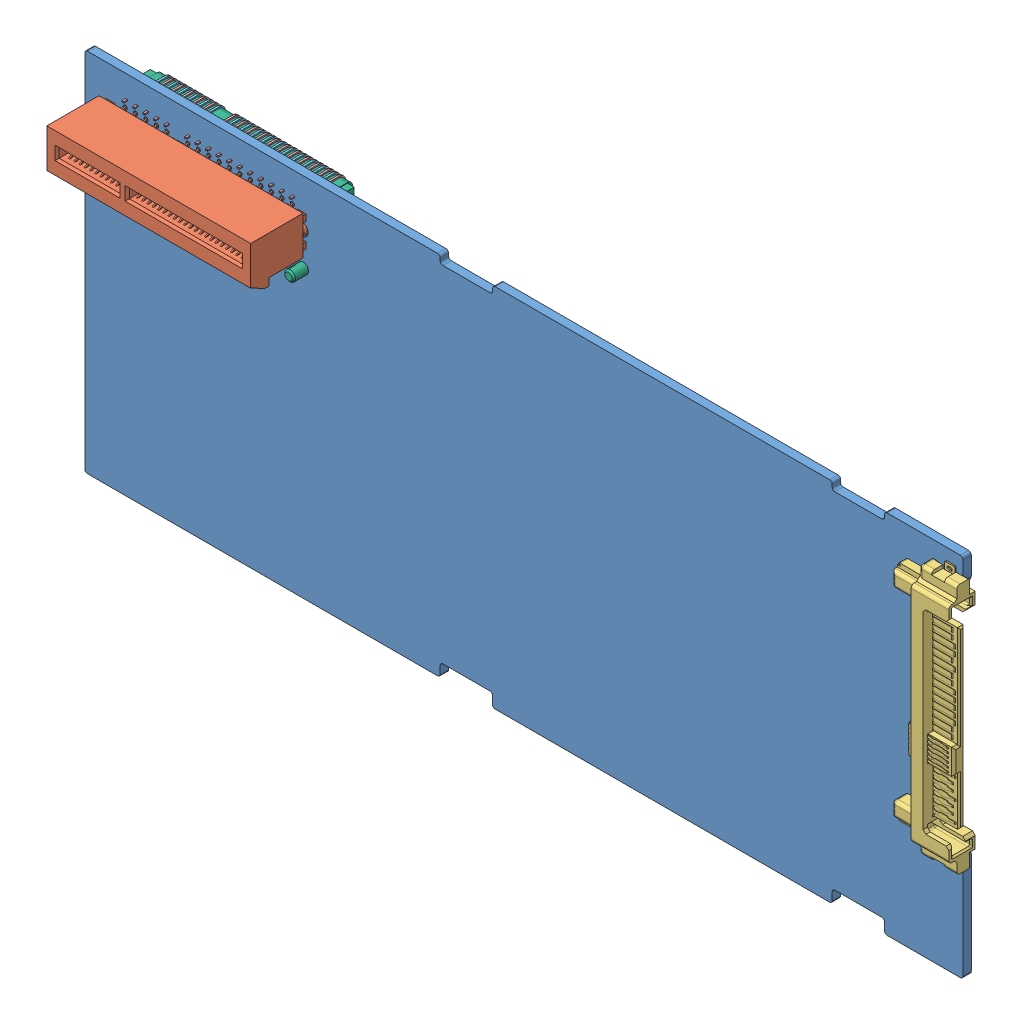
SolidWorks assembly u2CEM, configuration Default. Lengths in mm.
Overall size (169.53 63.5 22.05).
8 component instances, 6 part files, 9 mates.
Components (placement in the parent):
- u2CEM.step-1: u2CEM.step [Default] at origin size (168 63.5 1.6)
  - u2CEM PCB.step-1: u2CEM PCB.step [Default] at origin size (168 63.5 1.6)
- 10018783-x0xxx_64c.stp-1: 10018783-x0xxx_64c.stp [Default] at (230.235 -98.95 1.6) x (1 0.000053 0) z (0.000053 -1 0) size (39 15.4 8.8)
- 3d_model_psas4m213002xxx.stp-1: 3d_model_psas4m213002xxx.stp [Default] at (374.1 -116.95 3.6) x (0 1 0) z (0 0 -1) size (49.45 12.58 5.15)
- PCIE_064_02_F_D_RA-1: PCIE_064_02_F_D_RA [Default] at (235.4948 -101.7998 -5.8) x (-1 -0.000053 0) z (0 0 1) size (39.03 18.85 13.86)
  - PCIE_064_02_F_D_RA_3-1: PCIE_064_02_F_D_RA_3 [Default] at (6.9945 0 0) size (34 17.93 10.46)
  - PCIE_064_02_F_D_RA_5-1: PCIE_064_02_F_D_RA_5 [Default] at (6.9945 0 0) size (34 16.93 10.48)
  - PCIE_064_02_F_D_RA_7-1: PCIE_064_02_F_D_RA_7 [Default] at origin size (39.03 18.85 13.86)
Mates (geometry in assembly coordinates):
- Concentric1: concentric: cylinder of 10018783-x0xxx_64c.stp-1 through (230.385 -98.95 11.8728) axis (0 0 -1) radius 1.1; cylinder of u2CEM.step-1/u2CEM PCB.step-1 through (230.385 -98.95 -0.8) axis (0 0 1) radius 1.2
- Parallel1: parallel: plane of u2CEM.step-1/u2CEM PCB.step-1 through (212.5 -90 0) normal (-0.000053 1 0); plane of 10018783-x0xxx_64c.stp-1 through (235.2352 -102.6497 7.6) normal (0.000053 -1 0)
- Coincident1: coincident: plane of u2CEM.step-1/u2CEM PCB.step-1 through (298.8632 -124.9629 1.6) normal (0 0 1); plane of 10018783-x0xxx_64c.stp-1 through (216.9351 -101.2507 1.6) normal (0 0 -1)
- Concentric3: concentric: cylinder of u2CEM.step-1/u2CEM PCB.step-1 through (371.2 -136.42 -0.8) axis (0 0 1) radius 0.625; cylinder of 3d_model_psas4m213002xxx.stp-1 through (371.2 -136.42 2.0115) axis (0 0 -1) radius 0.5
- Parallel2: parallel: plane of u2CEM.step-1/u2CEM PCB.step-1 through (376 -100 0) normal (1 0 0); plane of 3d_model_psas4m213002xxx.stp-1 through (376.4 -116.95 3.6) normal (1 0 0)
- Coincident2: coincident: plane of u2CEM.step-1/u2CEM PCB.step-1 through (298.8632 -124.9629 1.6) normal (0 0 1); plane of 3d_model_psas4m213002xxx.stp-1 through (377.7 -140.95 1.6) normal (0 0 -1)
- Distance1: distance = 4 mm: plane of PCIE_064_02_F_D_RA-1/PCIE_064_02_F_D_RA_7-1 through (253.6999 -93.9978 -0.3199) normal (-0.000053 1 0); plane of u2CEM.step-1/u2CEM PCB.step-1 through (212.5 -90 0) normal (-0.000053 1 0)
- Distance2: distance = 4 mm: plane of u2CEM.step-1/u2CEM PCB.step-1 through (212 -159.5 0) normal (-1 0 0); line of PCIE_064_02_F_D_RA-1/PCIE_064_02_F_D_RA_7-1 through (216 -95.5508 -6.9449) axis (0 0 1)
- Coincident3: coincident: plane of u2CEM.step-1/u2CEM PCB.step-1 through (298.8632 -124.9629 0) normal (0 0 -1); plane of PCIE_064_02_F_D_RA-1/PCIE_064_02_F_D_RA_7-1 through (255.0009 -112.1477 0) normal (0 0 1)
